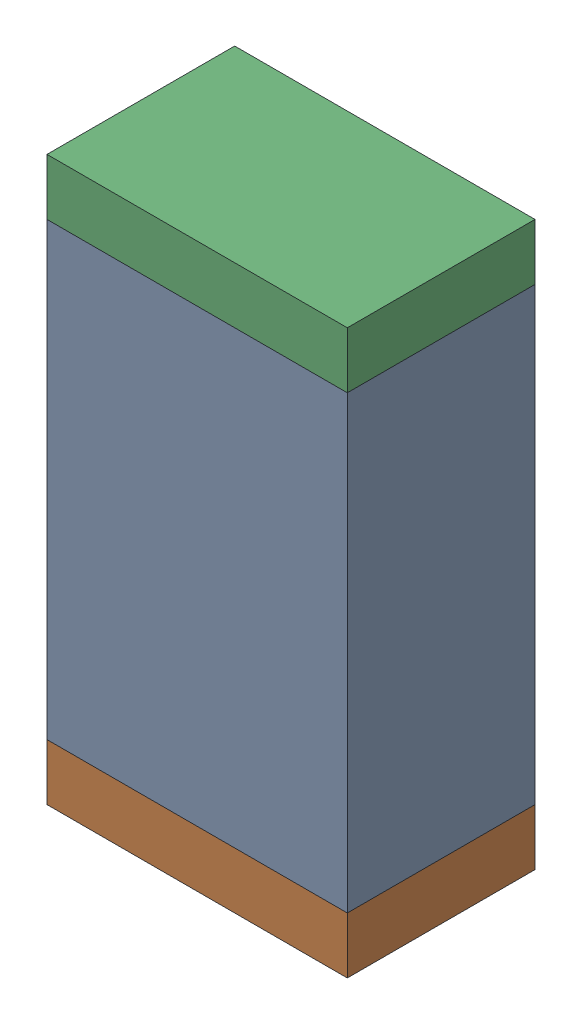
SolidWorks assembly R45, configuration Default. Lengths in mm.
Overall size (0.8 1.5 0.5).
6 component instances, 2 part files, 0 mates.
Components (placement in the parent):
- 810156976-1: 810156976 [Default] at (124.6 58 0) size (0.8 1.2 0.5)
  - Extruded_6-1: Extruded_6 [Default] at origin size (0.8 1.2 0.5)
- 810156592-1: 810156592 [Default] at (124.6 57.325 0) size (0.8 0.15 0.5)
  - Extruded_7-1: Extruded_7 [Default] at origin size (0.8 0.15 0.5)
- 810156592-2: 810156592 [Default] at (124.6 58.675 0) size (0.8 0.15 0.5)
  - Extruded_7-1: Extruded_7 [Default] at origin size (0.8 0.15 0.5)
